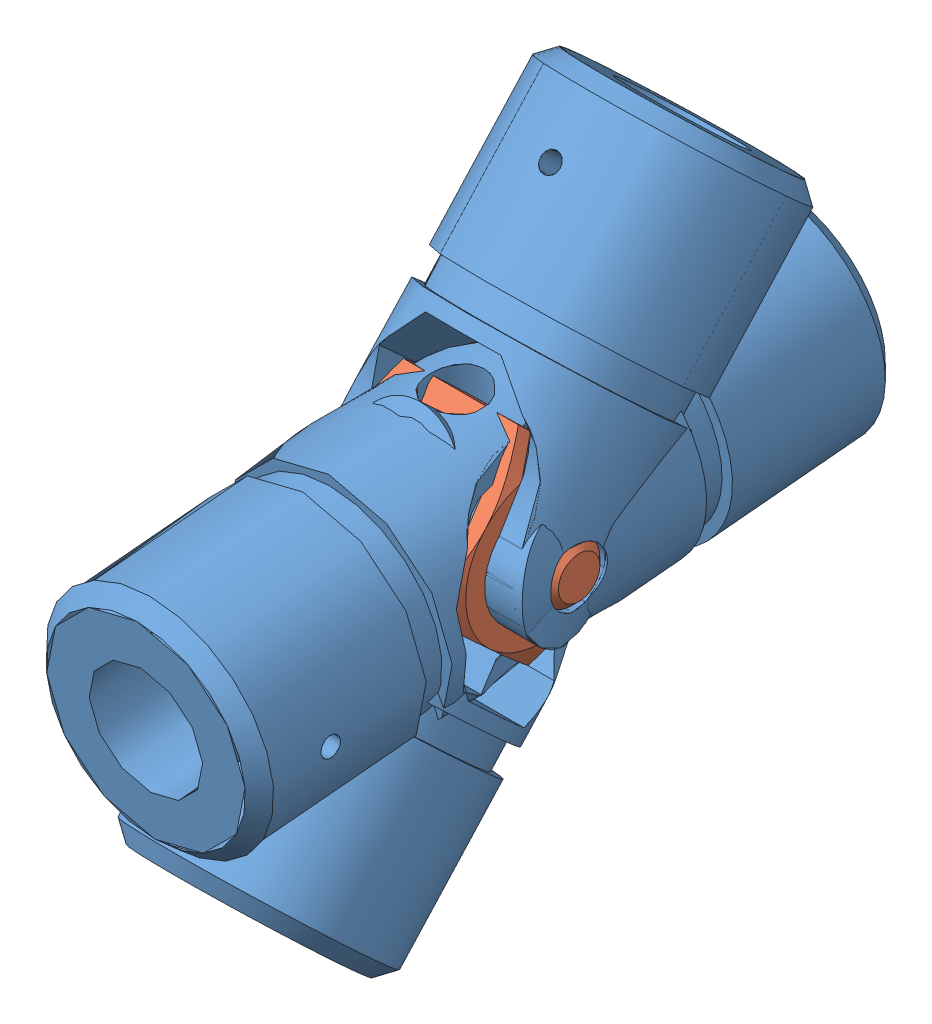
SolidWorks assembly Single U-Joint, for .75in Diameter x 1.1875in Deep Shaft, 6443K65, MMC, configuration Default. Lengths in mm.
Overall size (38.1 105.41 110.96).
3 component instances, 2 part files, 6 mates.
Components (placement in the parent):
- U-JOINT SHELL, .75 ID, 6443K940, MMC-2: U-JOINT SHELL, .75 ID, 6443K940, MMC [6443K94] at (-150.3307 73.9138 -33.5547) x (0 0.738493 -0.674261) z (1 0 0) size (107.95 38.1 38.1)
- U-JOINT X CORE, .75 ID, 6443K94, MMC-1: U-JOINT X CORE, .75 ID, 6443K94, MMC [Default] at (-150.3307 73.9138 -33.5547) x (-1 0 0) z (0 0.674261 0.738493) size (38.1 25.37 38.1)
- U-JOINT SHELL, .75 ID, 6443K940, MMC-3: U-JOINT SHELL, .75 ID, 6443K940, MMC [6443K94] at (-150.3307 73.9138 -33.5547) x (0 -0.090606 0.995887) z (0 0.995887 0.090606) size (107.95 38.1 38.1)
Mates (geometry in assembly coordinates):
- Concentric1: concentric anti-aligned: cylinder of U-JOINT SHELL, .75 ID, 6443K940, MMC-2 through (-150.3307 61.0691 -47.623) axis (0 0.674261 0.738493) radius 4.7625; cylinder of U-JOINT X CORE, .75 ID, 6443K94, MMC-1 through (-150.3307 86.7585 -19.4864) axis (0 -0.674261 -0.738493) radius 4.7625
- Coincident3: coincident anti-aligned: plane of U-JOINT SHELL, .75 ID, 6443K940, MMC-2 through (-169.3807 73.0848 -15.6178) normal (0 -0.674261 -0.738493); plane of U-JOINT X CORE, .75 ID, 6443K94, MMC-1 through (-150.3307 82.4684 -24.1852) normal (0 0.674261 0.738493)
- Coincident4: coincident anti-aligned: cylinder of U-JOINT X CORE, .75 ID, 6443K94, MMC-1 through (-131.2807 73.9138 -33.5547) axis (-1 0 0) radius 4.7625; circle of U-JOINT SHELL, .75 ID, 6443K940, MMC-3
- Coincident5: coincident anti-aligned: plane of U-JOINT X CORE, .75 ID, 6443K94, MMC-1 through (-163.018 91.8378 -32.7398) normal (-1 0 0); plane of U-JOINT SHELL, .75 ID, 6443K940, MMC-3 through (-163.018 56.0934 -47.9348) normal (1 0 0)
- Perpendicular4: perpendicular: plane of U-JOINT SHELL, .75 ID, 6443K940, MMC-3 through (-150.3307 57.2795 -60.9715) normal (0 -0.090606 0.995887)
- Concentric4: concentric anti-aligned: cylinder of U-JOINT SHELL, .75 ID, 6443K940, MMC-3 through (-150.3307 76.0714 -57.2692) axis (0 0.090606 -0.995887) radius 9.525
